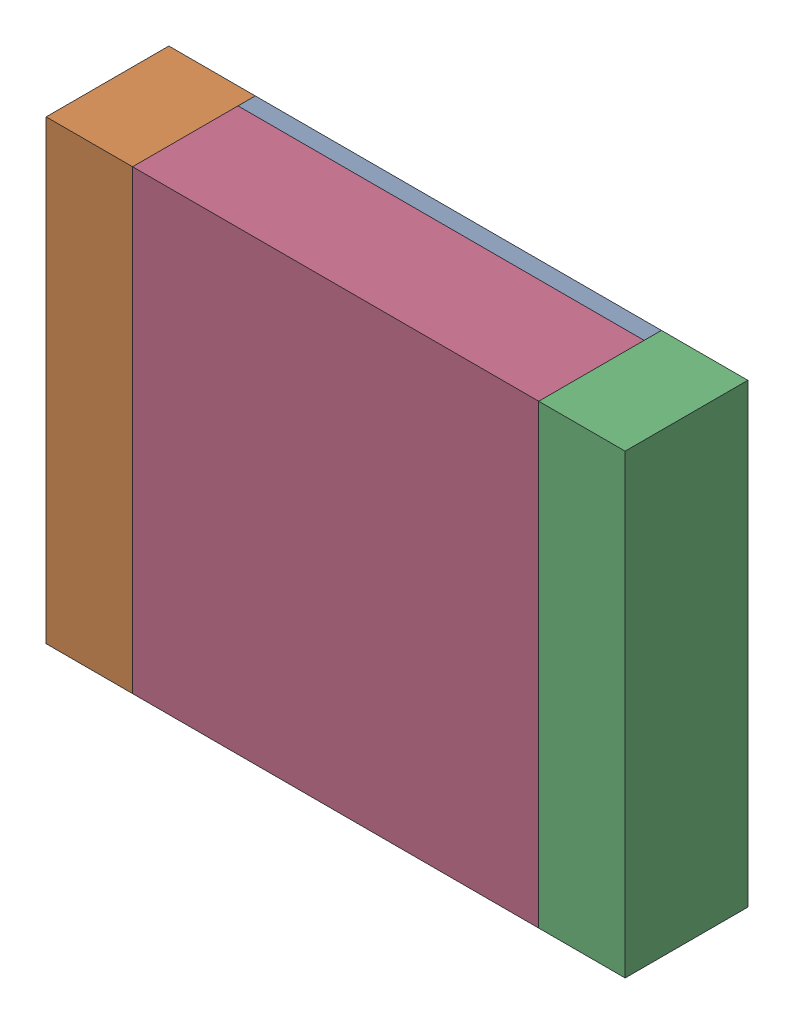
SolidWorks assembly R4, configuration 默认. Lengths in mm.
Overall size (3.35 2.64 0.71).
8 component instances, 3 part files, 0 mates.
Components (placement in the parent):
- 6241787936-1: 6241787936 [默认] at (37.719 24.511 -2.4014) size (2.35 2.64 0.1)
  - Extruded-6-1: Extruded-6 [默认] at origin size (2.35 2.64 0.1)
- 6241788416-1: 6241788416 [默认] at (36.294 24.511 -2.4014) size (0.5 2.64 0.71)
  - Extruded-7-1: Extruded-7 [默认] at origin size (0.5 2.64 0.71)
- 6241788416-2: 6241788416 [默认] at (39.144 24.511 -2.4014) size (0.5 2.64 0.71)
  - Extruded-7-1: Extruded-7 [默认] at origin size (0.5 2.64 0.71)
- 6241788736-1: 6241788736 [默认] at (37.719 24.511 -2.3014) size (2.35 2.64 0.61)
  - Extruded-8-1: Extruded-8 [默认] at origin size (2.35 2.64 0.61)
